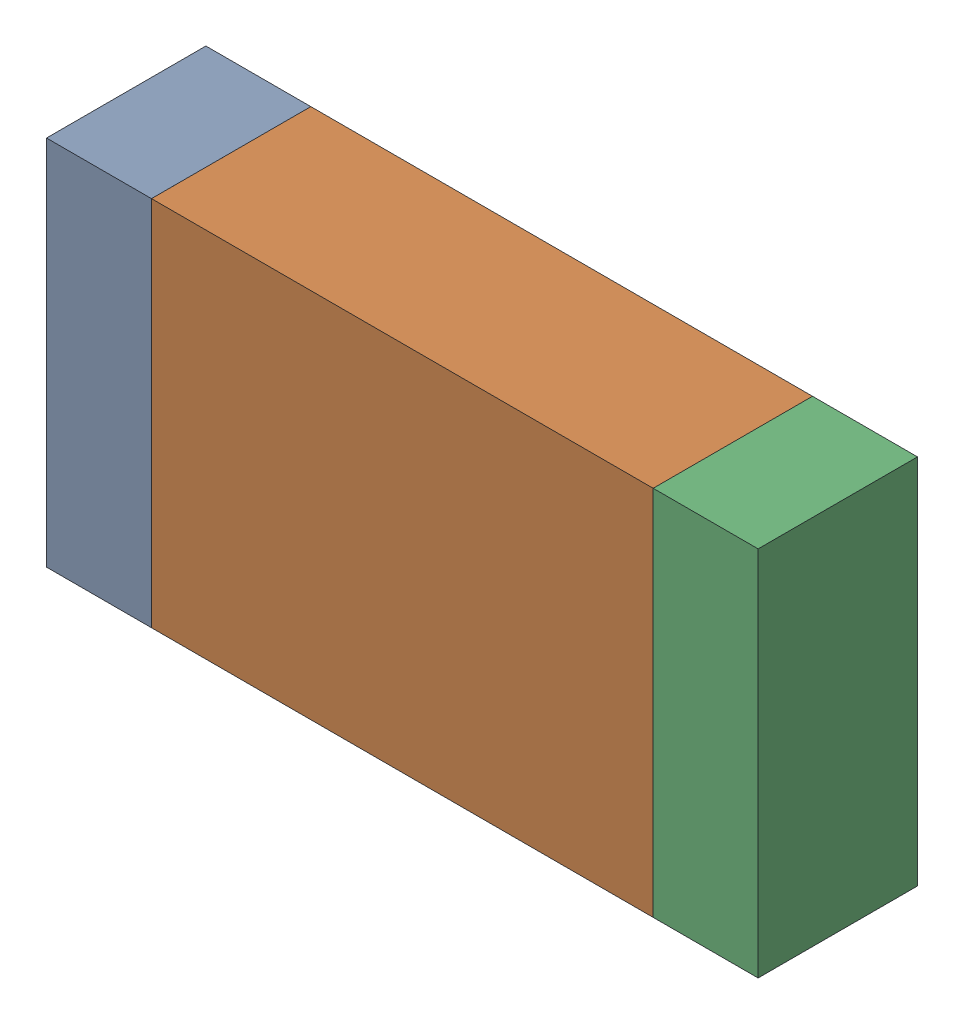
SolidWorks assembly R10-2, configuration Default. Lengths in mm.
Overall size (3.35 1.75 0.75).
6 component instances, 2 part files, 0 mates.
Components (placement in the parent):
- 959206760-2-1: 959206760-2 [Default] at (152.7506 83.5661 0) size (0.49 1.75 0.75)
  - Extruded-64-1: Extruded-64 [Default] at origin size (0.49 1.75 0.75)
- 959206896-2-1: 959206896-2 [Default] at (154.1781 83.5661 0) size (2.36 1.75 0.75)
  - Extruded-65-1: Extruded-65 [Default] at origin size (2.36 1.75 0.75)
- 959206760-2-2: 959206760-2 [Default] at (155.6056 83.5661 0) size (0.49 1.75 0.75)
  - Extruded-64-1: Extruded-64 [Default] at origin size (0.49 1.75 0.75)
